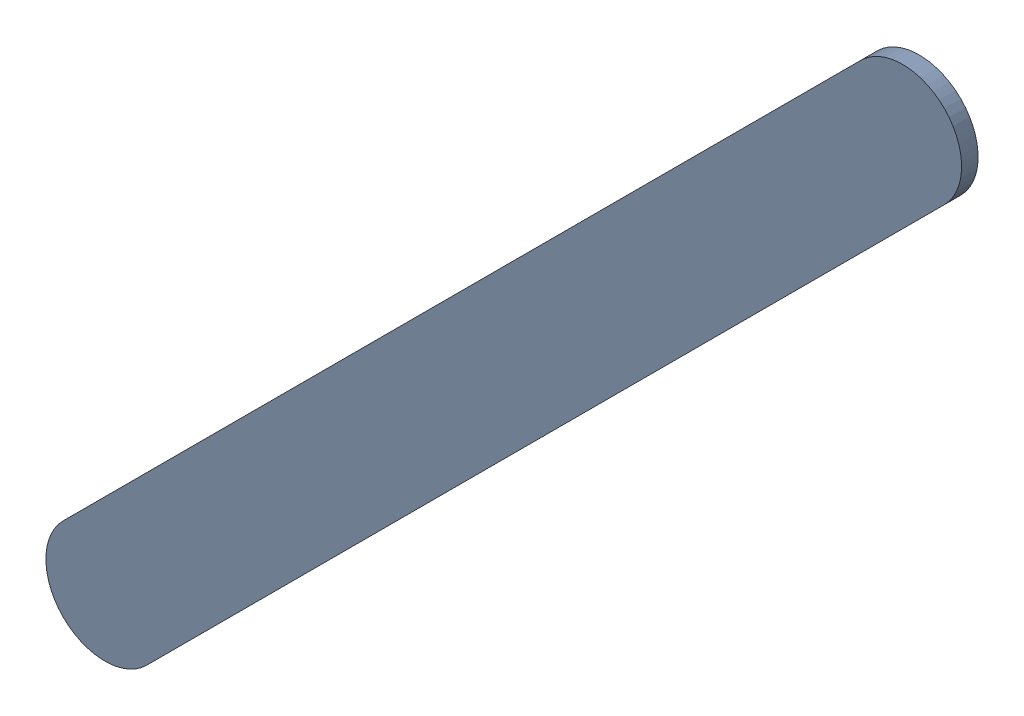
SolidWorks assembly Track (26.16mm,6.8mm)(27.878mm,8.518mm) on Top Layer, configuration Predeterminado. Lengths in mm.
Overall size (1.97 1.97 0.04).
2 component instances, 1 part files, 0 mates.
Components (placement in the parent):
- Track (26.16mm,6.8mm)(27.878mm,8.518mm) on Top Layer-1-1: Track (26.16mm,6.8mm)(27.878mm,8.518mm) on Top Layer-1 [Predeterminado] at (-68.317 -44.187 -0.0457) size (1.97 1.97 0.04)
  - Track (26.16mm,6.8mm)(27.878mm,8.518mm) on Top Layer-Part-1-1: Track (26.16mm,6.8mm)(27.878mm,8.518mm) on Top Layer-Part-1 [Predeterminado] at origin size (1.97 1.97 0.04)
